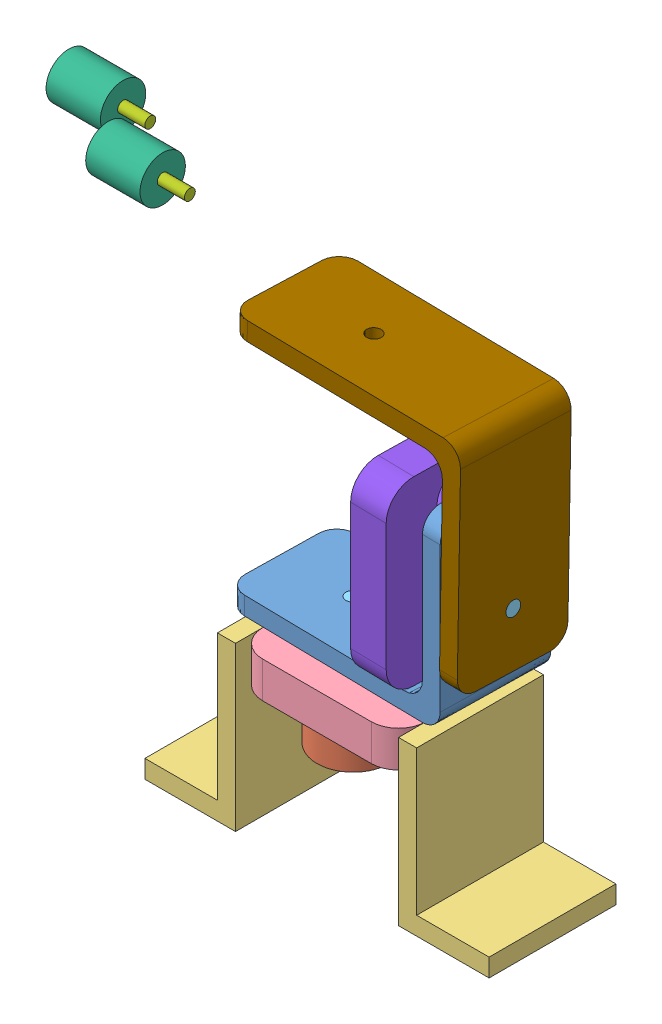
SolidWorks assembly Assemminubotmechanism, configuration Default. Lengths in mm.
Overall size (310.23 274.38 96.75).
14 component instances, 9 part files, 19 mates.
Components (placement in the parent):
- l link-1: l link [Default] at (-42.3774 20.615 73.0053) x (0.999834 0 0.018209) z (-0.018209 0 0.999834) size (120 100 60)
- motor-1: motor [Default] at (67.0581 70.615 105.0033) x (-0.999834 0 -0.018209) z (0.013603 -0.664777 -0.746918) size (50 40 40)
- support-1: support [Default] at (-82.9303 -79.385 68.7286) size (50 90 70)
- motor-2: motor [Default] at (-2.9303 10.615 103.7286) x (0 -1 0) z (-0.977702 0 -0.209998) size (50 40 40)
- support-2: support [Default] at (107.0697 -79.385 138.7286) x (-1 0 0) z (0 0 -1) size (50 90 70)
- motorholder-2: motorholder [Default] at (12.0697 -9.385 103.7286) x (1 0 0) z (0 1 0) size (90 70 20)
- motorshaft-1: motorshaft [Default] at (-2.9303 30.615 103.7286) x (0 0 -1) z (0 -1 0) size (8 8 20)
- encoder-1: encoder [Default] at (-203.1636 158.0191 60.5643) size (30 25 25)
- encoder-2: encoder [Default] at (-133.2054 182.4977 108.6527) size (30 25 25)
- motorshaft-2: motorshaft [Default] at (87.0548 70.615 105.3674) x (-0.006953 0.924225 0.381786) z (-0.999834 0 -0.018209) size (8 8 20)
- encodershaft-2: encodershaft [Default] at (-103.2054 182.4977 108.6527) x (0 0 -1) z (1 0 0) size (6 6 15)
- encodershaft-3: encodershaft [Default] at (-158.1636 158.0191 60.5643) x (0 0 1) z (-1 0 0) size (6 6 15)
- motorholder1-1: motorholder1 [Default] at (37.063 80.615 104.457) x (0 1 0) z (0.999834 0 0.018209) size (100 80 20)
- l link1-1: l link1 [Default] at (87.5915 40.1014 75.8949) x (0.000314 0.999851 -0.017268) z (-0.018206 0.017271 0.999685) size (120 130 60)
Mates (geometry in assembly coordinates):
- Coincident1: coincident anti-aligned: circle of motor-2; circle of motorshaft-1
- Coincident2: coincident anti-aligned: circle of motor-1; circle of motorshaft-2
- Coincident3: coincident anti-aligned: circle of encoder-1; circle of encodershaft-3
- Coincident6: coincident aligned: circle of encoder-2; circle of encodershaft-2
- Coincident8: coincident aligned: circle of l link-1; circle of motorshaft-2
- Concentric3: concentric anti-aligned: circle of motorshaft-1; circle of l link-1
- Coincident10: coincident aligned: plane of l link-1 through (-43.47 30.615 132.9953) normal (0 1 0); plane of motorshaft-1 through (-2.9303 30.615 103.7286) normal (0 1 0)
- Coincident11: coincident anti-aligned: cylinder of motor-2 through (-2.9303 -39.385 103.7286) axis (0 1 0) radius 20; circle of motorholder-2
- Coincident15: coincident anti-aligned: line of support-1 through (-32.9303 10.615 138.7286) axis (0 0 -1); line of motorholder-2 through (-32.9303 10.615 83.7286) axis (0 0 1)
- Coincident17: coincident anti-aligned: line of support-2 through (57.0697 10.615 68.7286) axis (0 0 1); line of motorholder-2 through (57.0697 10.615 123.7286) axis (0 0 -1)
- Coincident18: coincident anti-aligned: plane of support-2 through (57.0697 -79.385 68.7286) normal (-1 0 0); plane of motorholder-2 through (57.0697 10.615 123.7286) normal (1 0 0)
- Coincident23: coincident anti-aligned: cylinder of motor-1 through (17.0664 70.615 104.0928) axis (0.999834 0 0.018209) radius 20; circle of motorholder1-1
- Parallel4: parallel anti-aligned: plane of l link-1 through (-43.47 30.615 132.9953) normal (0 1 0); plane of motorholder1-1 through (57.5149 30.615 79.8253) normal (0 -1 0)
- Coincident27: coincident anti-aligned: plane of support-1 through (-32.9303 -79.385 138.7286) normal (1 0 0); plane of motorholder-2 through (-32.9303 10.615 123.7286) normal (-1 0 0)
- Coincident28: coincident aligned: plane of motor-2 through (-2.9303 10.615 103.7286) normal (0 1 0); plane of motorholder-2 through (-17.9303 10.615 123.7286) normal (0 1 0)
- Coincident29: coincident aligned: line of l link-1 through (56.5135 30.615 134.8162) axis (0.018209 0 -0.999834); line of motorholder1-1 through (56.6045 30.615 129.817) axis (0.018209 0 -0.999834)
- Coincident30: coincident aligned: circle of motorshaft-2; circle of l link1-1
- Coincident32: coincident aligned: plane of support-1 through (-82.9303 -79.385 138.7286) normal (0 0 1); plane of support-2 through (107.0697 -79.385 138.7286) normal (0 0 1)
- Width1: width anti-aligned: plane of motorholder-2 through (42.0697 10.615 68.7286) normal (0 0 -1); plane of motorholder-2 through (42.0697 10.615 138.7286) normal (0 0 1); plane of support-2 through (107.0697 -79.385 138.7286) normal (0 0 1); plane of support-1 through (-82.9303 -79.385 68.7286) normal (0 0 -1)
